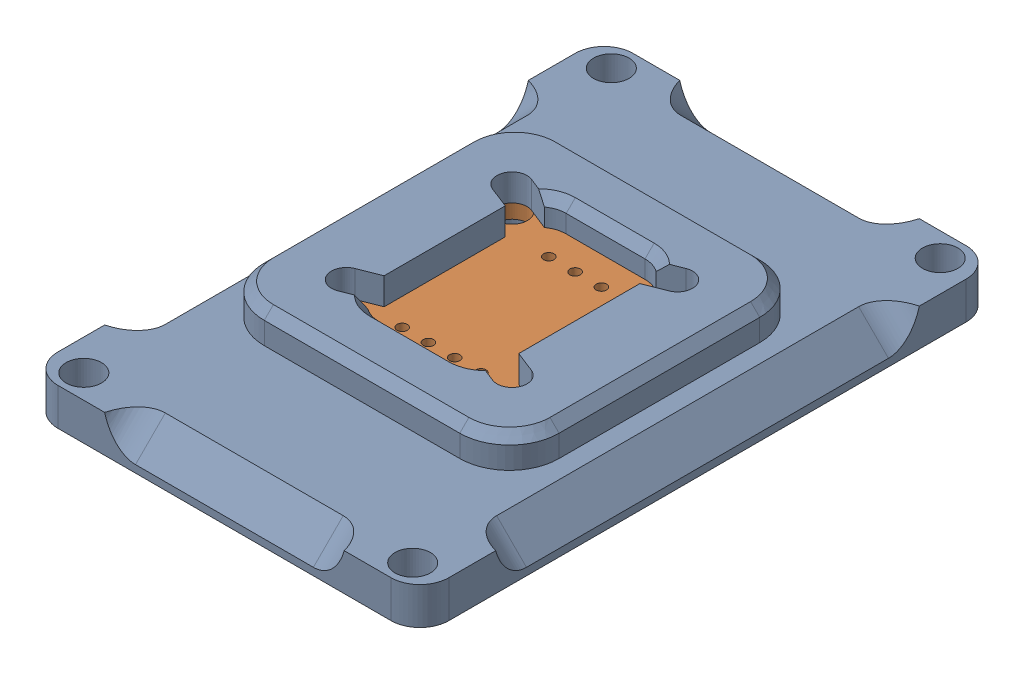
SolidWorks assembly Encoder_5__1, configuration Default. Lengths in mm.
Overall size (37.8 6.6 55.6).
2 component instances, 2 part files, 0 mates.
Components (placement in the parent):
- EncoderHousing_1-1: EncoderHousing_1 [Default] at (0 72.3086 693.01) x (1 0 0) z (0 -1 0) size (37.8 55.6 6.6)
- AS5600_1-1: AS5600_1 [Default] at (0 74.6086 693.01) x (1 0 0) z (0 0 -1) size (23 3.5 23)
